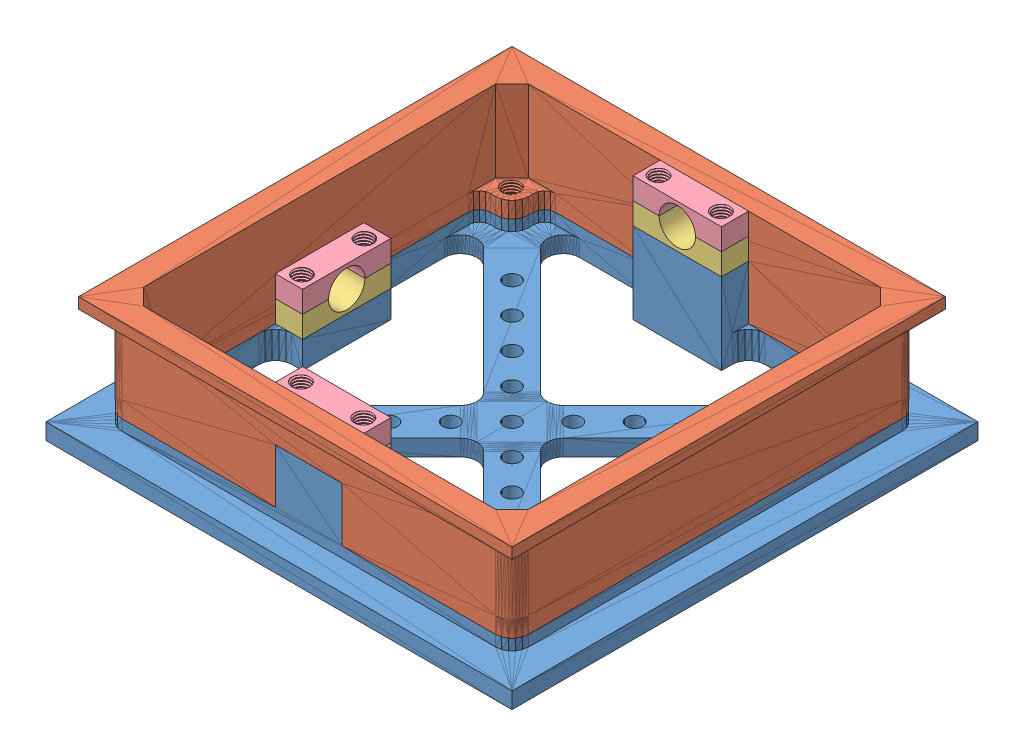
SolidWorks assembly AirCore10Assembly, configuration Default. Lengths in mm.
Overall size (86 23.23 86).
10 component instances, 4 part files, 26 mates.
Components (placement in the parent):
- Component1_v3-1: Component1_v3 [Default] at (11.6752 -56.6581 22.8365) x (-1 0 0) z (0 0 1) size (86 15.3 86)
- Component2_v3-1: Component2_v3 [Default] at (11.6752 -56.6581 22.8365) x (-1 0 0) z (0 0 1) size (80 18.18 80)
- RodHatBase-1: RodHatBase [Default] at (-31.3248 -33.6581 35.3365) x (-1 0 0) z (0 0 1) size (16.31 4.18 5)
- RodHatBase-2: RodHatBase [Default] at (-31.3248 -33.6581 101.3365) x (-1 0 0) z (0 0 1) size (16.31 4.18 5)
- RodHatBase-3: RodHatBase [Default] at (-61.8248 -43.6581 65.8365) x (0 0 1) z (1 0 0) size (16.31 4.18 5)
- RodHatBase-4: RodHatBase [Default] at (4.1752 -43.6581 65.8365) x (0 0 1) z (1 0 0) size (16.31 4.18 5)
- RodHatTop-1: RodHatTop [Default] at (-31.3248 -29.6581 35.3365) size (16.31 4.18 5)
- RodHatTop-2: RodHatTop [Default] at (-31.3248 -29.6581 101.3365) size (16.31 4.18 5)
- RodHatTop-3: RodHatTop [Default] at (-61.8248 -39.6581 65.8365) x (0 0 -1) z (1 0 0) size (16.31 4.18 5)
- RodHatTop-4: RodHatTop [Default] at (4.1752 -39.6581 65.8365) x (0 0 -1) z (1 0 0) size (16.31 4.18 5)
Mates (geometry in assembly coordinates):
- Coincident1: coincident aligned: line of Component1_v3-1 through (-37.4798 -45.6581 103.3365) axis (-1 0 0); line of Component2_v3-1 through (-37.4798 -45.6581 103.3365) axis (-1 0 0)
- Coincident2: coincident: point of Component1_v3-1; point of Component2_v3-1
- Coincident3: coincident aligned: line of Component1_v3-1 through (-25.1698 -35.6581 103.3365) axis (-1 0 0); line of Component2_v3-1 through (-25.1698 -35.6581 103.3365) axis (-1 0 0)
- Coincident4: coincident anti-aligned: line of Component1_v3-1 through (-39.4798 -35.6581 35.3365) axis (1 0 0); line of RodHatBase-1 through (-23.1698 -35.6581 35.3365) axis (-1 0 0)
- Coincident5: coincident: point of Component1_v3-1; point of RodHatBase-1
- Coincident6: coincident anti-aligned: line of Component1_v3-1 through (-23.1698 -35.6581 35.3365) axis (0 0 -1); line of RodHatBase-1 through (-23.1698 -35.6581 30.3365) axis (0 0 1)
- Coincident7: coincident anti-aligned: line of Component1_v3-1 through (-23.1698 -35.6581 101.3365) axis (0 0 -1); line of RodHatBase-2 through (-23.1698 -35.6581 96.3365) axis (0 0 1)
- Coincident8: coincident aligned: line of Component1_v3-1 through (-23.1698 -35.6581 96.3365) axis (-1 0 0); line of RodHatBase-2 through (-23.1698 -35.6581 96.3365) axis (-1 0 0)
- Coincident9: coincident anti-aligned: line of Component1_v3-1 through (-61.8248 -45.6581 73.9915) axis (0 0 -1); line of RodHatBase-3 through (-61.8248 -45.6581 57.6815) axis (0 0 1)
- Coincident10: coincident: point of Component1_v3-1; point of RodHatBase-3
- Coincident11: coincident aligned: line of Component1_v3-1 through (-0.8248 -45.6581 57.6815) axis (0 0 1); line of RodHatBase-4 through (-0.8248 -45.6581 57.6815) axis (0 0 1)
- Coincident12: coincident: point of Component1_v3-1; point of RodHatBase-4
- Concentric1: concentric aligned: circle of RodHatBase-1; circle of RodHatTop-1
- Coincident14: coincident aligned: line of RodHatBase-1 through (-39.4798 -31.6581 30.3365) axis (0 0 1); line of RodHatTop-1 through (-39.4798 -31.6581 30.3365) axis (0 0 1)
- Coincident15: coincident anti-aligned: line of RodHatBase-1 through (-34.6798 -31.6581 35.3365) axis (-1 0 0); line of RodHatTop-1 through (-39.4798 -31.6581 35.3365) axis (1 0 0)
- Parallel1: parallel anti-aligned: line of Component2_v3-1 through (1.1752 -27.6581 101.3365) axis (-1 0 0); line of RodHatTop-2 through (-39.4798 -27.6581 101.3365) axis (1 0 0)
- Concentric2: concentric aligned: circle of RodHatBase-2; circle of RodHatTop-2
- Coincident18: coincident anti-aligned: line of RodHatBase-2 through (-23.1698 -31.6581 96.3365) axis (-1 0 0); line of RodHatTop-2 through (-27.9698 -31.6581 96.3365) axis (1 0 0)
- Coincident23: coincident: point of RodHatBase-2; point of RodHatTop-2
- Coincident24: coincident: point of RodHatBase-2; point of RodHatTop-2
- Coincident25: coincident aligned: line of RodHatBase-3 through (-66.8248 -41.6581 73.9915) axis (1 0 0); line of RodHatTop-3 through (-66.8248 -41.6581 73.9915) axis (1 0 0)
- Concentric3: concentric aligned: circle of RodHatBase-3; circle of RodHatTop-3
- Coincident27: coincident: point of RodHatBase-3; point of RodHatTop-3
- Coincident28: coincident aligned: line of RodHatBase-4 through (-0.8248 -41.6581 73.9915) axis (1 0 0); line of RodHatTop-4 through (-0.8248 -41.6581 73.9915) axis (1 0 0)
- Concentric4: concentric aligned: circle of RodHatBase-4; circle of RodHatTop-4
- Coincident30: coincident: point of RodHatBase-4; point of RodHatTop-4
